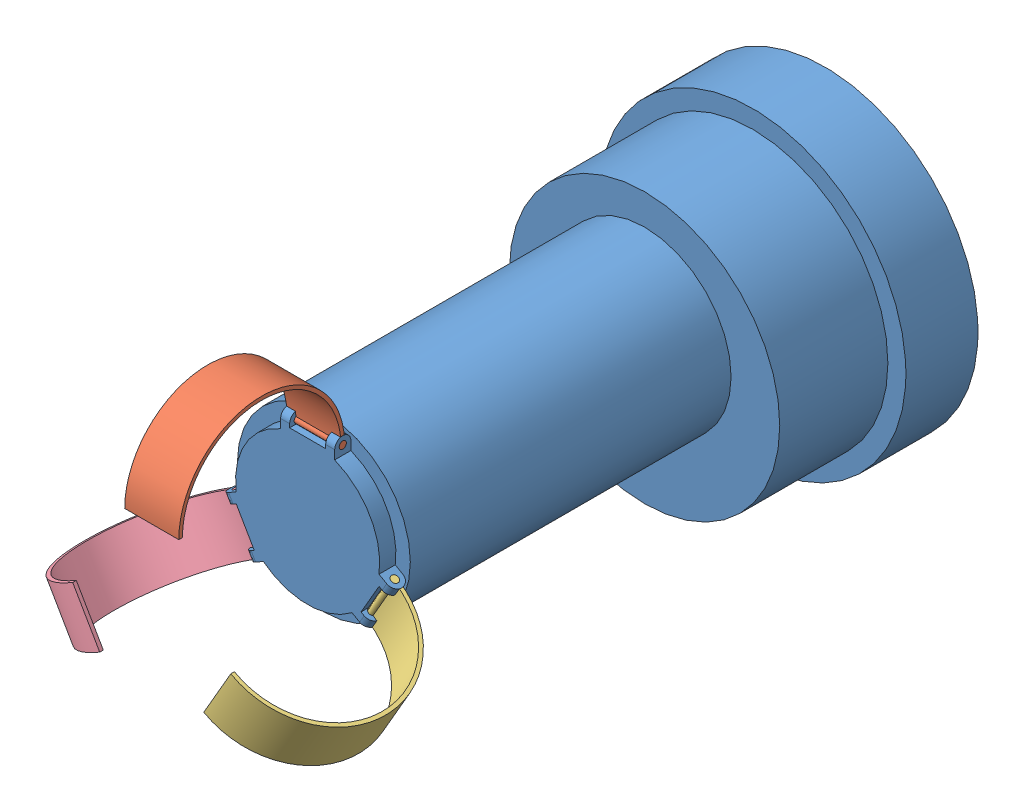
SolidWorks assembly Kirigami_gripper_allstl_gazebo, configuration ﾃﾞﾌｫﾙﾄ. Lengths in mm.
Overall size (85 91.5 186.75).
4 component instances, 4 part files, 9 mates.
Components (placement in the parent):
- kirigami_gripper_base-1: kirigami_gripper_base [ﾃﾞﾌｫﾙﾄ] at (6.3187 -3.2764 71.75) size (85 85 143.5)
- finger_1-1: finger_1 [ﾃﾞﾌｫﾙﾄ] at (13.8187 22.7236 213) x (0 1 0) z (-1 0 0) size (33 46.5 15)
- finger_2-1: finger_2 [ﾃﾞﾌｫﾙﾄ] at (20.7552 -15.2715 213) x (0.866025 -0.5 0) z (0.5 0.866025 0) size (33 46.5 15)
- finger_3-1: finger_3 [ﾃﾞﾌｫﾙﾄ] at (-15.6178 -2.2812 213) x (-0.866025 -0.5 0) z (0.5 -0.866025 0) size (33 46.5 15)
Mates (geometry in assembly coordinates):
- 一致1: coincident aligned: circle of kirigami_gripper_base-1; cylinder of fingger_1-1 through (-1.1813 22.7236 213) axis (1 0 0) radius 1
- 一致2: coincident aligned: plane of kirigami_gripper_base-1 through (13.8187 11.7236 210.75) normal (1 0 0); plane of fingger_1-1 through (13.8187 22.7236 213) normal (1 0 0)
- 同心円1: concentric anti-aligned: cylinder of kirigami_gripper_base-1 through (-6.6879 -62.8044 213) axis (0.5 0.866025 0) radius 1; cylinder of finger_2-1 through (28.2552 -2.2812 213) axis (-0.5 -0.866025 0) radius 1
- 一致3: coincident aligned: plane of kirigami_gripper_base-1 through (11.2289 -9.7715 215.25) normal (-0.5 -0.866025 0); plane of finger_2-1 through (20.7552 -15.2715 213) normal (-0.5 -0.866025 0)
- 同心円2: concentric anti-aligned: cylinder of kirigami_gripper_base-1 through (-38.7308 37.7517 213) axis (0.5 -0.866025 0) radius 1; cylinder of finger_3-1 through (-8.1178 -15.2715 213) axis (-0.5 0.866025 0) radius 1
- 一致4: coincident aligned: plane of kirigami_gripper_base-1 through (-6.0916 3.2188 210.75) normal (-0.5 0.866025 0); plane of finger_3-1 through (-15.6178 -2.2812 213) normal (-0.5 0.866025 0)
- 一致5: coincident: point of finger_1-1; point of assembly
- 一致7: coincident: point of finger_2-1; point of assembly
- 一致8: coincident: point of finger_3-1; point of assembly
